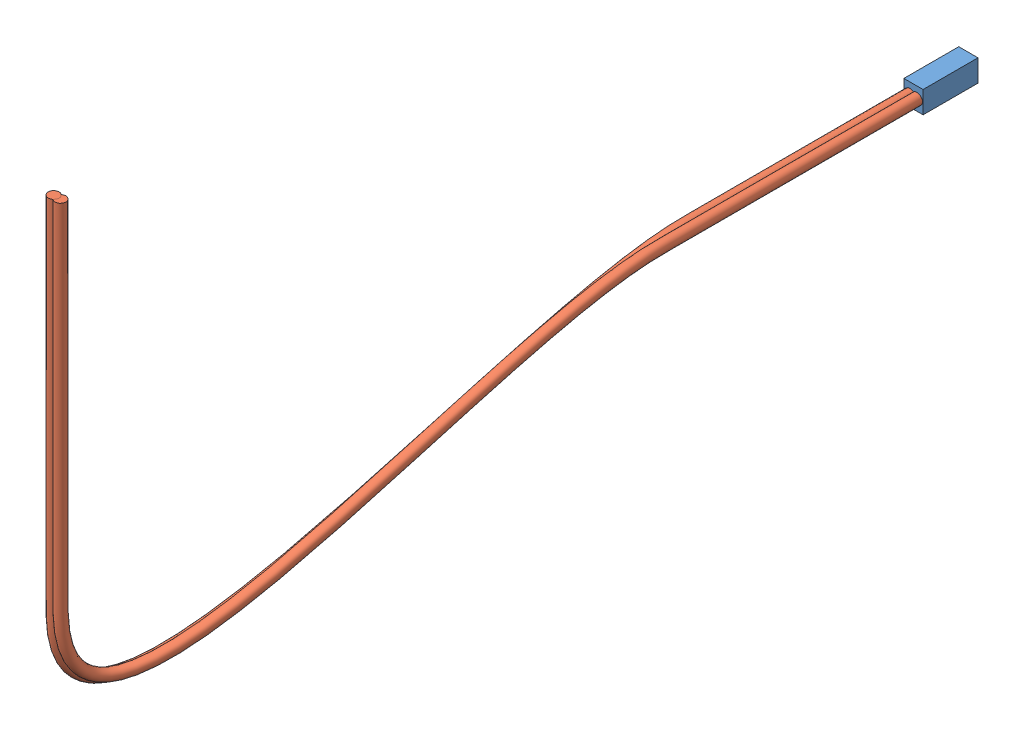
SolidWorks assembly Harness_3-CABLE_HARNESSING_ASSEMBLY, configuration Default. Lengths in mm.
Overall size (25.15 81.02 147.65).
3 component instances, 3 part files, 0 mates.
Components (placement in the parent):
- 02_PIN-1: 02_PIN [Default] at (2.0703 9.5684 -141.1129) size (3.5 4 20)
- Cable^Harness_3-CABLE_HARNESSING_ASSEMBLY-1: Cable^Harness_3-CABLE_HARNESSING_ASSEMBLY [Default] at origin size (25.15 81.02 138.4) (virtual)
- Flattened_Cable^Harness_3-CABLE_HARNESSING_ASSEMBLY-1: Flattened_Cable^Harness_3-CABLE_HARNESSING_ASSEMBLY [Default] at origin (suppressed, hidden, virtual)
